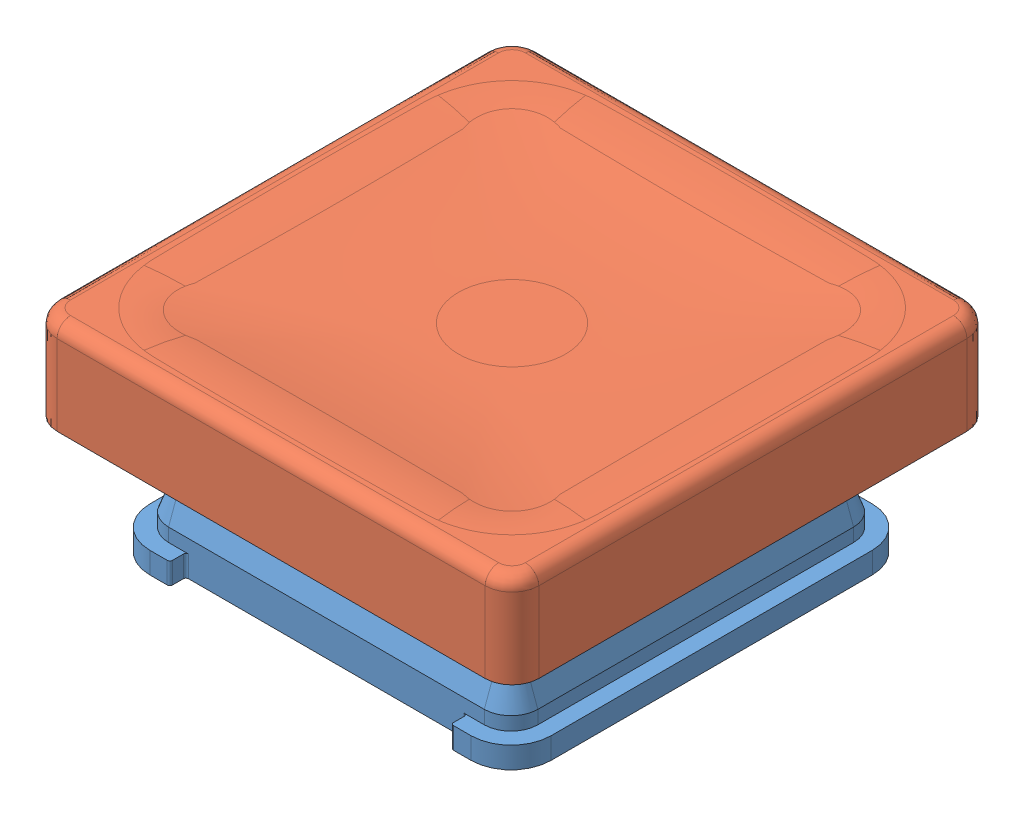
SolidWorks assembly Assemblage1, configuration Défaut. Lengths in mm.
Overall size (19.89 7.9 19.77).
2 component instances, 2 part files, 2 mates.
Components (placement in the parent):
- Kailh LP Choc Burnt Orange-1: Kailh LP Choc Burnt Orange [Default] at (0.8041 -2.6273 15) size (15 5.9 15)
- Kailh LP Keycap-1: Kailh LP Keycap [Default] at (0.8237 1.3727 14.9848) x (0 0 -1) z (1 0 0) size (19.77 4.5 19.89)
Mates (geometry in assembly coordinates):
- Parallèle1: parallel anti-aligned: plane of Kailh LP Choc Burnt Orange-1 through (-1.3959 2.8727 20.1) normal (0 1 0); plane of Kailh LP Keycap-1 through (8.8237 2.8727 6.9848) normal (0 -1 0)
- Coïncidente3: coincident anti-aligned: line of Kailh LP Choc Burnt Orange-1 through (-0.9057 2.8727 12.9598) axis (1 0 0); line of Kailh LP Keycap-1 through (2.5237 2.8727 12.9598) axis (-1 0 0)
